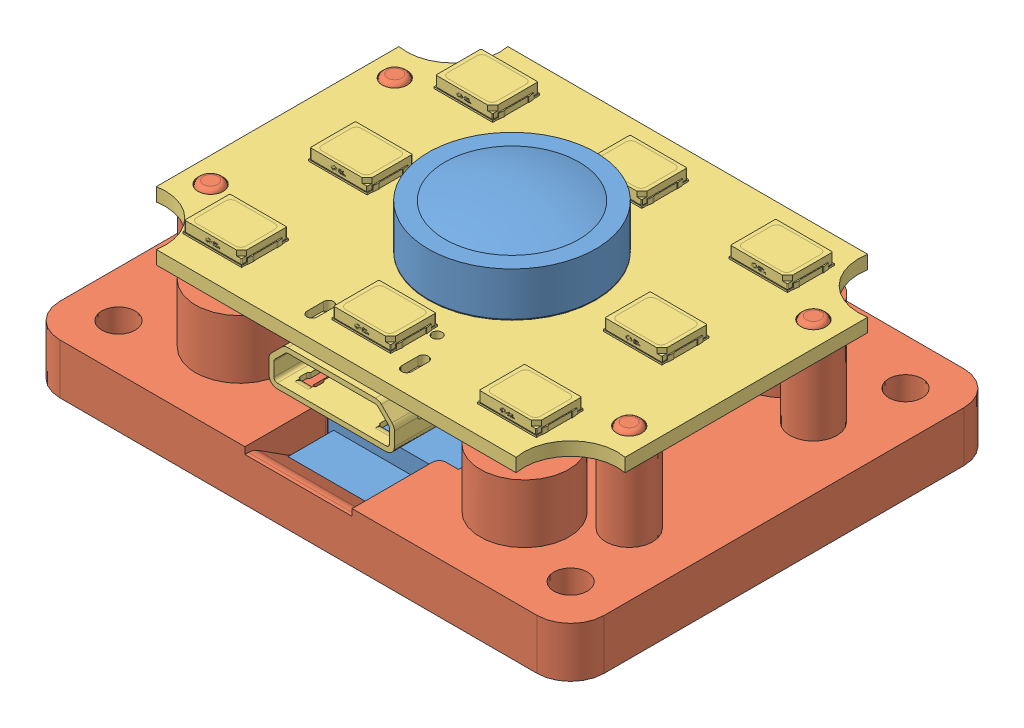
SolidWorks assembly Perception_Module-160-2, configuration 默认. Lengths in mm.
Overall size (100.3 60.76 53.5).
3 component instances, 3 part files, 3 mates.
Components (placement in the parent):
- camera(ZERO-v1.0)-160-2-1: camera(ZERO-v1.0)-160-2 [默认] at (0 1 0) size (10 10.55 17.65)
- base-160-2-1: base-160-2 [默认] at origin size (100.3 57.71 53.5)
- LED-1: LED [默认] at (-14.0001 6.6999 10.5) x (1 0 0) z (0 1 0) size (27.99 21.34 4.17)
Mates (geometry in assembly coordinates):
- 重合17: coincident anti-aligned: plane of base-160-2-1 through (12.5 7.5 5.5) normal (0 1 0); plane of LED-1 through (-0.0001 7.5 0) normal (0 -1 0)
- 同心13: concentric anti-aligned: cylinder of base-160-2-1 through (12.5 8.5 5.5) axis (0 -1 0) radius 0.725; cylinder of LED-1 through (12.5 6.6999 5.5) axis (0 1 0) radius 0.75
- 同心14: concentric anti-aligned: cylinder of base-160-2-1 through (12.5 8.5 -5.5) axis (0 -1 0) radius 0.725; cylinder of LED-1 through (12.5 6.6999 -5.5) axis (0 1 0) radius 0.75
